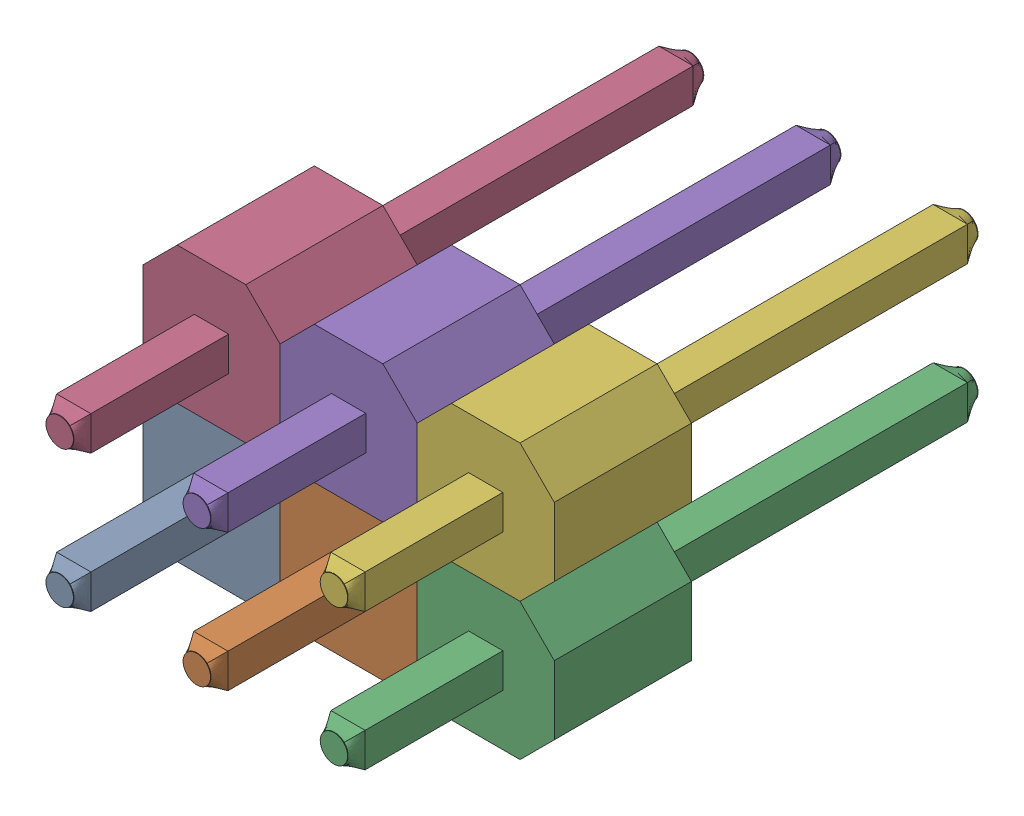
SolidWorks assembly Male Header 2x3 Pin, configuration Default. Lengths in mm.
Overall size (7.62 5.08 11.76).
6 component instances, 1 part files, 0 mates.
Components (placement in the parent):
- Male Header Pin-1: Male Header Pin [Default] at (-66.5496 11.8341 27.5639) size (2.54 2.54 11.76)
- Male Header Pin-2: Male Header Pin [Default] at (-64.0096 11.8341 27.5639) size (2.54 2.54 11.76)
- Male Header Pin-3: Male Header Pin [Default] at (-61.4696 11.8341 27.5639) size (2.54 2.54 11.76)
- Male Header Pin-4: Male Header Pin [Default] at (-66.5496 14.3741 27.5639) size (2.54 2.54 11.76)
- Male Header Pin-5: Male Header Pin [Default] at (-64.0096 14.3741 27.5639) size (2.54 2.54 11.76)
- Male Header Pin-6: Male Header Pin [Default] at (-61.4696 14.3741 27.5639) size (2.54 2.54 11.76)
